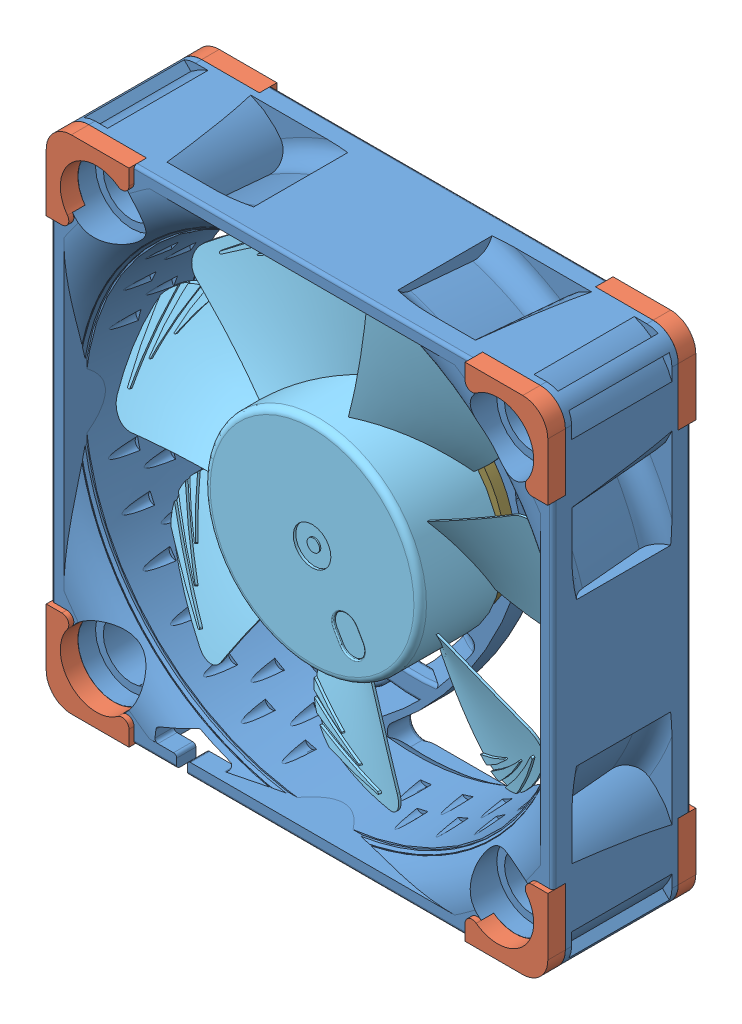
SolidWorks assembly NF-A4x10 FLX, configuration Predeterminado. Lengths in mm.
Overall size (43.47 43.5 12.76).
34 component instances, 19 part files, 30 mates.
Components (placement in the parent):
- Case-1: Case [Predeterminado] at origin size (40.18 40.19 12.76)
- Silent block-1: Silent block [Predeterminado] at (-16 16 10) size (6.6 6.6 1.4)
- Silent block-2: Silent block [Predeterminado] at (16 16 10) x (0 -1 0) z (0 0 1) size (6.6 6.6 1.4)
- Silent block-3: Silent block [Predeterminado] at (16 -16 10) x (-1 0 0) z (0 0 1) size (6.6 6.6 1.4)
- Silent block-4: Silent block [Predeterminado] at (-16 -16 10) x (0 1 0) z (0 0 1) size (6.6 6.6 1.4)
- Silent block-5: Silent block [Predeterminado] at (-16 16 -0.4) size (6.6 6.6 1.4)
- Silent block-6: Silent block [Predeterminado] at (16 16 -0.4) x (0 -1 0) z (0 0 1) size (6.6 6.6 1.4)
- Silent block-7: Silent block [Predeterminado] at (16 -16 -0.4) x (-1 0 0) z (0 0 1) size (6.6 6.6 1.4)
- Silent block-8: Silent block [Predeterminado] at (-16 -16 -0.4) x (0 1 0) z (0 0 1) size (6.6 6.6 1.4)
- Magnet-1: Magnet [Predeterminado] at (0 0 0.4) size (4.08 4.08 0.9)
- Back plate-1: Back plate [Predeterminado] at origin size (15.2 15.2 0.4)
- Impeller-1: Impeller [Predeterminado] at (0 0 10.2) x (0.232084 -0.972696 0) z (0 0 1) size (36.12 36.07 6.94)
- Magnetic screen-1: Magnetic screen [Predeterminado] at (0 0 3.7) x (0.411264 -0.911516 0) z (0 0 1) size (16.85 16.85 6)
- Rotor-1: Rotor [Predeterminado] at (0 0 3.7) x (-0.165519 0.986207 0) z (0 0 -1) size (16.45 16.45 6.1)
- Shaft-1: Shaft [Predeterminado] at (0 0 9.8) x (0.165519 -0.986207 0) z (0 0 1) size (2.38 2.37 7.5)
- Oil Bearing-1: Oil Bearing [Predeterminado] at (0 0 2) x (1 0 0) z (0 0 -1) size (5 5 5)
  - Bearing-1: Bearing [Predeterminado] at origin size (5 5 5)
  - Bearing gasket-1: Bearing gasket [Predeterminado] at (0 0 -1.3) size (2 2 0.5)
  - Oil-1: Oil [Predeterminado] at (0 0 -4.5) size (4 4 2.7)
  - Bearing gasket-2: Bearing gasket [Predeterminado] at (0 0 -4.5) size (2 2 0.5)
- Brushless motor-1: Brushless motor [Predeterminado] at (0 0 2) size (16 16 8.48)
  - Board-1: Board [Predeterminado] at origin size (16 16 0.8)
  - Stator-1: Stator [Predeterminado] at (0 0 3.55) size (11.93 12 5.5)
  - Hall Effect sensor-1: Hall Effect sensor [WE] at (-5.3023 -0.9391 0) x (-0.233503 0.972356 0) z (-0.972356 -0.233503 0) size (6.3 1.6 2.6)
  - Controller-1: Controller [Predeterminado] at (5.1574 2.3195 0) x (0.319288 -0.947658 0) z (0.947658 0.319288 0) size (4.81 0.99 3)
  - Coil-1: Coil [Predeterminado] at (0 -5.01 1.29) x (-1 0 0) z (0 1 0) size (2.38 5.38 1.58)
  - Coil-2: Coil [Predeterminado] at (-4.3388 -2.505 1.29) x (-0.5 0.866025 0) z (0.866025 0.5 0) size (2.38 5.38 1.58)
  - Coil-3: Coil [Predeterminado] at (-4.3388 2.505 1.29) x (0.5 0.866025 0) z (0.866025 -0.5 0) size (2.38 5.38 1.58)
  - Coil-4: Coil [Predeterminado] at (0 5.01 1.29) x (1 0 0) z (0 -1 0) size (2.38 5.38 1.58)
  - Coil-5: Coil [Predeterminado] at (4.3388 2.505 1.29) x (0.5 -0.866025 0) z (-0.866025 -0.5 0) size (2.38 5.38 1.58)
  - Coil-6: Coil [Predeterminado] at (4.3388 -2.505 1.29) x (-0.5 -0.866025 0) z (-0.866025 0.5 0) size (2.38 5.38 1.58)
  - Pieza2^Brushless motor-1: Pieza2^Brushless motor [Predeterminado] at origin size (10.72 12.51 6.88) (virtual)
  - Pieza3^Brushless motor-1: Pieza3^Brushless motor [Predeterminado] at (0 0 0.8) size (4.1 0.74 1.7) (virtual)
- Wires^NF-A4x10 FLX-1: Wires^NF-A4x10 FLX [Predeterminado] at (0 0 2) x (-1 0 0) z (0 0 -1) size (13.5 12.74 7.88) (virtual)
Mates (geometry in assembly coordinates):
- Coincidente1: coincident aligned: plane of Case-1 through (0 0 0) normal (0 0 1)
- Coincidente2: coincident aligned: plane of Case-1 through (0 0 0) normal (0 1 0)
- Coincidente3: coincident aligned: plane of Case-1 through (0 0 0) normal (1 0 0)
- Concéntrica1: concentric anti-aligned: cylinder of Case-1 through (-16 16 8.6) axis (0 0 1) radius 2.875; cylinder of Silent block-1 through (-16 16 11.4) axis (0 0 -1) radius 2.875
- Coincidente4: coincident anti-aligned: plane of Case-1 through (-13.4 -18 11) normal (-1 0 0); plane of Silent block-1 through (-13.4 20 11.4) normal (1 0 0)
- Coincidente5: coincident anti-aligned: plane of Case-1 through (-18 -18 10) normal (0 0 1); plane of Silent block-1 through (-18.7563 13.9563 10) normal (0 0 -1)
- Concéntrica2: concentric aligned: cylinder of Case-1 through (0 0 1.4) axis (0 0 -1) radius 2.1; cylinder of Magnet-1 through (0 0 1.3) axis (0 0 -1) radius 2.04
- Coincidente6: coincident aligned: plane of Case-1 through (0 0 0.4) normal (0 0 -1); plane of Magnet-1 through (0 0 0.4) normal (0 0 -1)
- Concéntrica3: concentric aligned: cylinder of Magnet-1 through (0 0 1.3) axis (0 0 -1) radius 2.04; cylinder of Back plate-1 through (0 0 0.4) axis (0 0 -1) radius 7.6
- Coincidente7: coincident anti-aligned: plane of Case-1 through (0 0 0.4) normal (0 0 -1); plane of Back plate-1 through (0 0 0.4) normal (0 0 1)
- Coincidente8: coincident aligned: plane of Magnet-1 through (0 0 0.4) normal (0 1 0)
- Coincidente9: coincident aligned: plane of Back plate-1 through (0 0 0) normal (0 1 0)
- Concéntrica4: concentric anti-aligned: cone of Case-1 through (0 0 0) axis (0 0 -1); cylinder of Impeller-1 through (0 0 10.2) axis (0 0 1) radius 8.625
- Concéntrica5: concentric anti-aligned: cylinder of Impeller-1 through (0 0 10.2) axis (0 0 1) radius 8.425; cylinder of Gasket-1 through (0 0 9.7) axis (0 0 -1) radius 8.425
- Coincidente10: coincident aligned: plane of Impeller-1 through (2.0017 -8.3895 3.7) normal (0 0 -1); plane of Gasket-1 through (0 0 3.7) normal (0 0 -1)
- Concéntrica6: concentric aligned: cylinder of Gasket-1 through (0 0 9.7) axis (0 0 -1) radius 8.225; cylinder of Rotor-1 through (0 0 9.8) axis (0 0 -1) radius 8.225
- Coincidente11: coincident aligned: plane of Gasket-1 through (0 0 3.7) normal (0 0 -1); plane of Rotor-1 through (0 0 3.7) normal (0 0 -1)
- Concéntrica7: concentric aligned: cylinder of Impeller-1 through (0 0 9.8) axis (0 0 1) radius 1; cylinder of Shaft-1 through (0 0 2.3) axis (0 0 1) radius 1
- Coincidente12: coincident anti-aligned: plane of Impeller-1 through (0 0 9.8) normal (0 0 -1); plane of Shaft-1 through (0 0 9.8) normal (0 0 1)
- Distancia1: distance = 0.8 mm aligned: plane of Impeller-1 through (0 0 10.2) normal (0 0 1); plane of Case-1 through (-18.7563 -13.9563 11) normal (0 0 1)
- Concéntrica8: concentric anti-aligned: cylinder of Case-1 through (0 0 1.2) axis (0 0 1) radius 3.1; cylinder of Oil Bearing-1/Bearing-1 through (0 0 2) axis (0 0 -1) radius 2.5
- Coincidente13: coincident anti-aligned: plane of Case-1 through (-8.3202 -3.0887 2) normal (0 0 1); plane of Oil Bearing-1/Bearing-1 through (-1.5 0 2) normal (0 0 -1)
- Concéntrica9: concentric aligned: cylinder of Oil Bearing-1/Bearing-1 through (0 0 2) axis (0 0 -1) radius 2.5; cylinder of Brushless motor-1/Stator-1 through (0 0 8.3) axis (0 0 -1) radius 2.5
- Coincidente14: coincident anti-aligned: plane of Case-1 through (-8.3202 -3.0887 2) normal (0 0 1); plane of Brushless motor-1/Board-1 through (0 0 2) normal (0 0 -1)
- Ancho3: width anti-aligned: plane of Case-1 through (-4.4294 1.6359 11.6693) normal (-0.972356 -0.233503 0); plane of Case-1 through (-7.3427 1.3477 11.6693) normal (0.972356 0.233503 0); plane of Brushless motor-1/Hall Effect sensor-1 through (-3.5362 -2.7261 0.4) normal (0.972356 0.233503 0); plane of Brushless motor-1/Hall Effect sensor-1 through (-6.0643 -3.3332 0.4) normal (-0.972356 -0.233503 0)
- Ancho4: width anti-aligned: plane of Brushless motor-1/Hall Effect sensor-1 through (-6.0643 -3.3332 0.4) normal (0.233503 -0.972356 0); plane of Brushless motor-1/Hall Effect sensor-1 through (-7.0684 0.848 0.4) normal (-0.233503 0.972356 0); plane of Case-1 through (-3.2619 -3.2258 11.6693) normal (-0.233503 0.972356 0); plane of Case-1 through (-5.435 1.8058 11.6693) normal (0.233503 -0.972356 0)
- EnPosición1: in place: plane of ? through (0 0 2) normal (0 0 -1); plane of Wires^NF-A4x10 FLX-1 through (0 0 2) normal (0 0 -1); moOrthogonalPlaneRef_w of ? through (0 0 2) normal (0 0 -1); plane of Wires^NF-A4x10 FLX-1 through (0 0 2) normal (0 1 0); plane of ? through (0 0 2) normal (0 0 -1); plane of Wires^NF-A4x10 FLX-1 through (0 0 2) normal (-1 0 0); plane of ? through (0 0 2) normal (0 0 -1); unknown of Wires^NF-A4x10 FLX-1
- Coincidente16: coincident aligned: plane of ?; plane of ?
- Coincidente17: coincident aligned: moOrthogonalPlaneRef_w of Brushless motor-1/Board-1 through (0 0 2) normal (0 1 0); plane of Pieza4^NF-A4x10 FLX-1 through (0 0 2) normal (0 1 0)
- Coincidente18: coincident anti-aligned: moOrthogonalPlaneRef_w of Brushless motor-1/Board-1 through (0 0 2) normal (1 0 0); plane of Pieza4^NF-A4x10 FLX-1 through (0 0 2) normal (-1 0 0)
